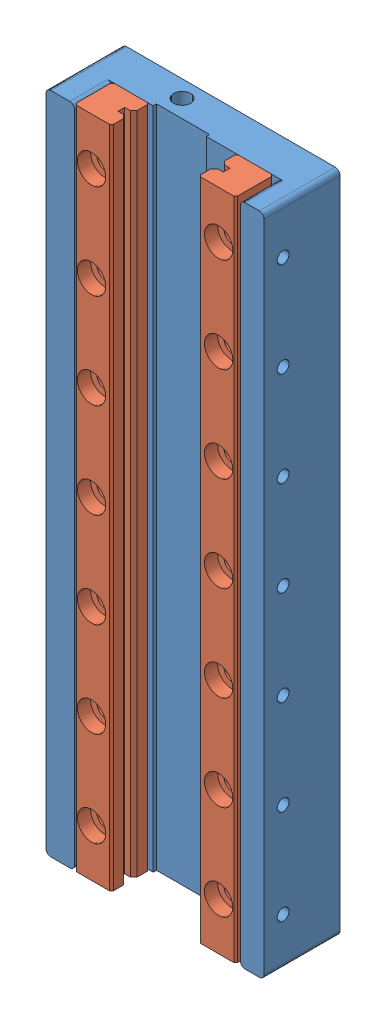
SolidWorks assembly SLC-1770-S-NM, configuration Default. Lengths in mm.
Overall size (23 70 8).
4 component instances, 2 part files, 0 mates.
Components (placement in the parent):
- SLC-1770-S-NM-1: SLC-1770-S-NM [Default] at (-5.8046 -26.3657 66) size (23 70 8)
- Führung_1770_nm-1: Führung_1770_nm [Default] at (-1.3958 8.6343 71.3882) x (1 0 0) z (0 -1 0) size (17 4 70)
  - Schiene_1770-1: Schiene_1770 [Default] at (-4.4089 -1.3882 35) size (3.9 4 70)
  - Schiene_1770-2: Schiene_1770 [Default] at (12.5911 -1.3882 -35) x (-1 0 0) z (0 0 -1) size (3.9 4 70)
